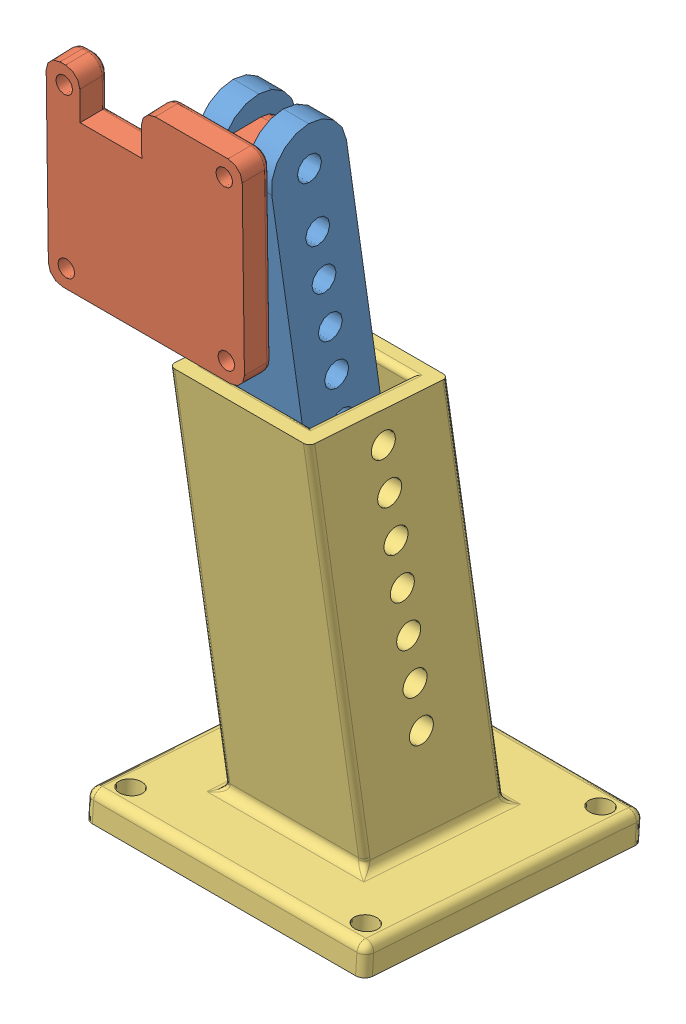
SolidWorks assembly Camera Mount - Built, configuration Default. Lengths in mm.
Overall size (50 131.73 68.08).
3 component instances, 3 part files, 5 mates.
Components (placement in the parent):
- Camera Mount - Upper Stand-2: Camera Mount - Upper Stand [Default] at (-90.1622 18.9434 44.5942) size (13.6 70 22.41)
- Camera Mount - Camera Base-1: Camera Mount - Camera Base [Default] at (-89.9122 81.7116 71.31) x (1 0 0) z (0 -0.999915 -0.013059) size (35 26.5 35)
- Camera Mount - Stand-2: Camera Mount - Stand [默认] at (-88.6622 -30.5067 38.5856) x (1 0 0) z (0 0.069141 0.997607) size (50 75 52.5)
Mates (geometry in assembly coordinates):
- 同心15: concentric: Camera Mount - Upper Stand-2, Camera Mount - Camera Base-1
- 重合2: coincident: Camera Mount - Upper Stand-2, Camera Mount - Camera Base-1
- 距离1: distance: Camera Mount - Stand-2, Camera Mount - Upper Stand-2
- 同心16: concentric: Camera Mount - Upper Stand-2, Camera Mount - Stand-2
- 平行2: parallel: Camera Mount - Upper Stand-2, Camera Mount - Stand-2
